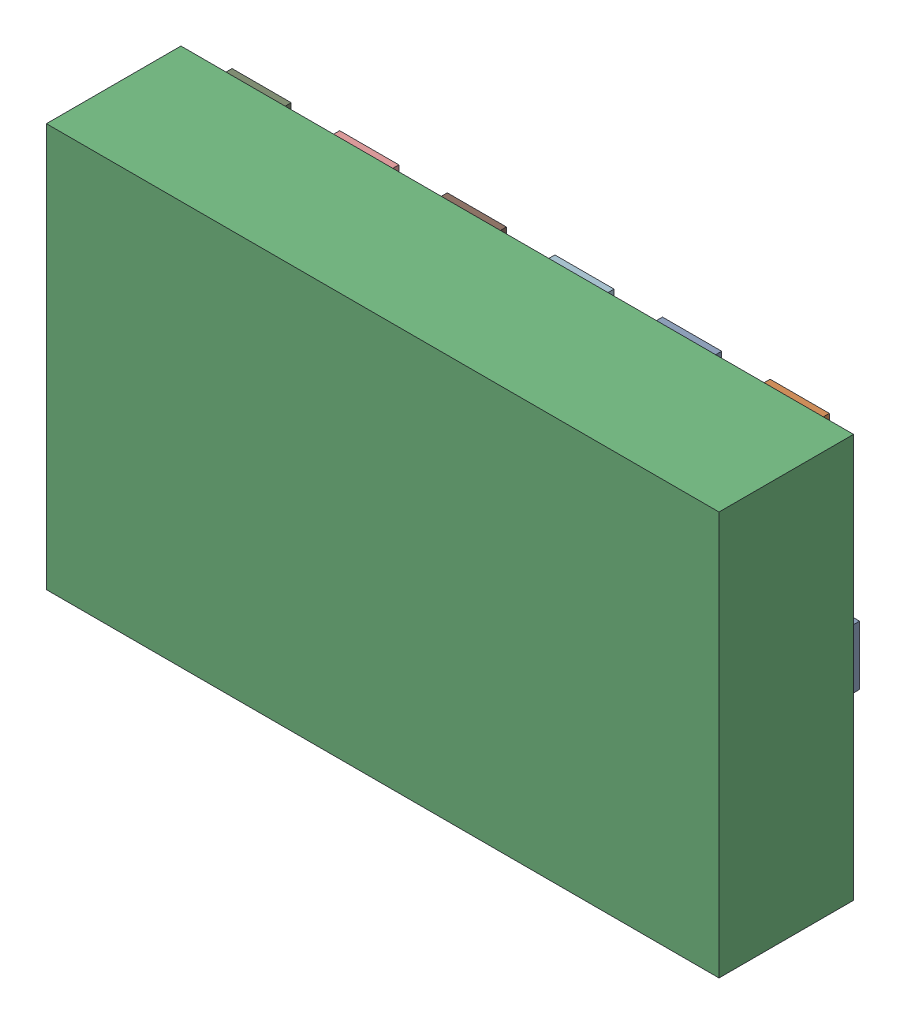
SolidWorks assembly ADXL345, configuration Predeterminado. Lengths in mm.
Overall size (5 3 1.1).
17 component instances, 15 part files, 0 mates.
Components (placement in the parent):
- 6074687440-1: 6074687440 [Predeterminado] at (21 57 0) x (0 -1 0) z (0 0 1) size (3 5 1.1)
  - 6074687440-subassembly-1-1: 6074687440-subassembly-1 [Predeterminado] at origin size (2.89 4.89 0.1)
    - Pins-1: Pins [Predeterminado] at origin size (0.44 0.86 0.1)
    - Pins-1-1: Pins-1 [Predeterminado] at origin size (0.87 0.44 0.1)
    - Pins-2-1: Pins-2 [Predeterminado] at origin size (0.87 0.44 0.1)
    - Pins-3-1: Pins-3 [Predeterminado] at origin size (0.87 0.44 0.1)
    - Pins-4-1: Pins-4 [Predeterminado] at origin size (0.87 0.44 0.1)
    - Pins-5-1: Pins-5 [Predeterminado] at origin size (0.87 0.44 0.1)
    - Pins-6-1: Pins-6 [Predeterminado] at origin size (0.87 0.44 0.1)
    - Pins-7-1: Pins-7 [Predeterminado] at origin size (0.44 0.86 0.1)
    - Pins-8-1: Pins-8 [Predeterminado] at origin size (0.87 0.44 0.1)
    - Pins-9-1: Pins-9 [Predeterminado] at origin size (0.87 0.44 0.1)
    - Pins-10-1: Pins-10 [Predeterminado] at origin size (0.87 0.44 0.1)
    - Pins-11-1: Pins-11 [Predeterminado] at origin size (0.87 0.44 0.1)
    - Pins-12-1: Pins-12 [Predeterminado] at origin size (0.87 0.44 0.1)
    - Pins-13-1: Pins-13 [Predeterminado] at origin size (0.87 0.44 0.1)
  - Body-1: Body [Predeterminado] at (0 0 0.1) size (3 5 1)
